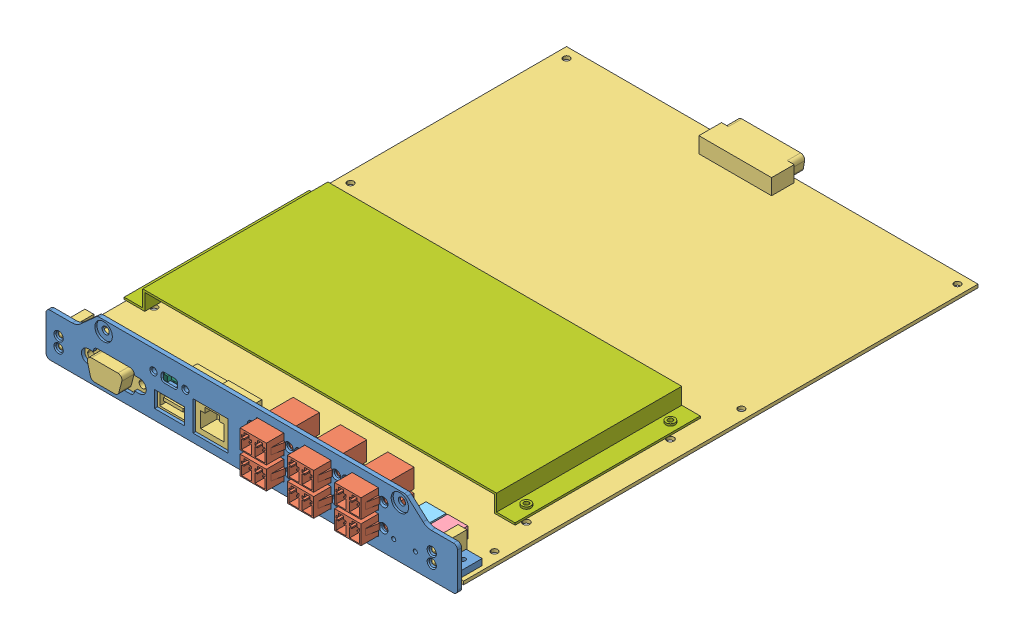
SolidWorks assembly FOD-MODULE-ASSY_ASM, configuration Standard. Lengths in mm.
Overall size (200 30 265.8).
13 component instances, 7 part files, 0 mates.
Components (placement in the parent):
- FOD-IO-PANEL-1: FOD-IO-PANEL [Standard] at (0 -2.9 1) size (200 30 14)
- CONN-LC-TYPE-SCREW-1: CONN-LC-TYPE-SCREW [Standard] at (109 12 11.3) x (-1 0 0) z (0 0 1) size (22 9.3 25.8)
- CONN-LC-TYPE-SCREW-2: CONN-LC-TYPE-SCREW [Standard] at (132 12 11.3) x (-1 0 0) z (0 0 1) size (22 9.3 25.8)
- CONN-LC-TYPE-SCREW-3: CONN-LC-TYPE-SCREW [Standard] at (155 12 11.3) x (-1 0 0) z (0 0 1) size (22 9.3 25.8)
- CONN-LC-TYPE-SCREW-4: CONN-LC-TYPE-SCREW [Standard] at (109 23 11.3) x (-1 0 0) z (0 0 1) size (22 9.3 25.8)
- CONN-LC-TYPE-SCREW-5: CONN-LC-TYPE-SCREW [Standard] at (132 23 11.3) x (-1 0 0) z (0 0 1) size (22 9.3 25.8)
- CONN-LC-TYPE-SCREW-6: CONN-LC-TYPE-SCREW [Standard] at (155 23 11.3) x (-1 0 0) z (0 0 1) size (22 9.3 25.8)
- FOD-MAIN-BD-1: FOD-MAIN-BD [Standard] at origin size (200 15.1 262)
  - FOD-MAIN-BD_3-1: FOD-MAIN-BD_3 [Standard] at origin size (200 15.1 262)
  - FOD-MAIN-BD_2-1: FOD-MAIN-BD_2 [Standard] at origin size (9.8 5.5 18.1)
  - FOD-MAIN-BD-1: FOD-MAIN-BD [Standard] at origin size (9.8 5.5 18.1)
- SLIDE-SWITCH-1: SLIDE-SWITCH [Standard] at (60 14.5 -5) size (19 6 10.5)
- FOD-BD-COVER-1: FOD-BD-COVER [Standard] at (100 7.6 -120) size (190 9 90)
